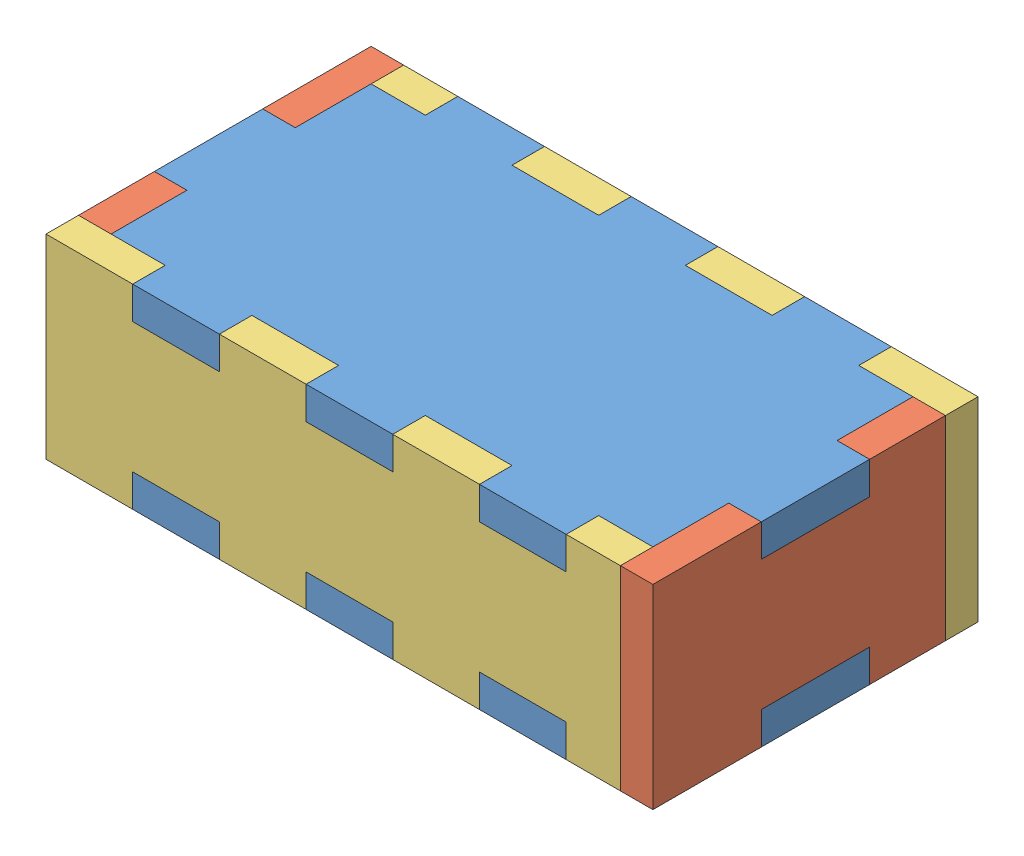
SolidWorks assembly DC-DC CC-CV, configuration Default. Lengths in mm.
Overall size (56 18 30).
6 component instances, 3 part files, 18 mates.
Components (placement in the parent):
- unten_oben-1: unten_oben [unten] at (-9.1679 54.5344 97.0759) size (56 3 30)
- rechts_links-1: rechts_links [rechts] at (46.8327 72.5344 97.0759) x (0 0 -1) z (0 1 0) size (27 3 18)
- vorne_hinten-1: vorne_hinten [Vorne] at (-9.1679 72.5341 97.0759) x (1 0 0) z (0 1 0) size (53 3 18)
- unten_oben-3: unten_oben [oben] at (-9.1679 69.5341 97.0759) size (56 3 30)
- rechts_links-4: rechts_links [links] at (-9.1679 72.5344 67.076) x (0 0 1) z (0 1 0) size (27 3 18)
- vorne_hinten-4: vorne_hinten [Default] at (46.8327 72.5341 67.076) x (-1 0 0) z (0 1 0) size (53 3 18)
Mates (geometry in assembly coordinates):
- Deckungsgleich14: coincident aligned: plane of unten_oben-1 through (-9.1679 57.5344 89.4649) normal (-1 0 0); plane of ? through (-9.1679 123.5344 97.0097) normal (-1 0 0)
- Deckungsgleich17: coincident aligned: plane of unten_oben-1 through (-9.1679 54.5344 97.0759) normal (0 -1 0); plane of ? through (-9.1679 54.5344 51.737) normal (0 -1 0)
- Deckungsgleich19: coincident aligned: plane of unten_oben-1 through (-0.7135 57.5344 97.0097) normal (0 0 1); plane of ? through (-9.1679 62.2019 97.0097) normal (0 0 1)
- Deckungsgleich54: coincident aligned: plane of unten_oben-1 through (-9.1679 54.5344 97.0759) normal (0 -1 0); plane of vorne_hinten-1 through (-9.1679 54.5344 94.0759) normal (0 -1 0)
- Deckungsgleich56: coincident aligned: plane of unten_oben-1 through (-1.1669 57.5344 97.0759) normal (0 0 1); plane of vorne_hinten-1 through (-9.1679 72.5341 97.0759) normal (0 0 1)
- Deckungsgleich57: coincident aligned: plane of vorne_hinten-1 through (-9.1679 72.5341 94.0759) normal (-1 0 0); plane of unten_oben-3 through (-9.1679 72.5341 77.0762) normal (-1 0 0)
- Deckungsgleich58: coincident aligned: plane of vorne_hinten-1 through (-9.1679 72.5341 94.0759) normal (0 1 0); plane of unten_oben-3 through (-9.1679 72.5341 97.0759) normal (0 1 0)
- Deckungsgleich59: coincident aligned: plane of vorne_hinten-1 through (-9.1679 72.5341 97.0759) normal (0 0 1); plane of unten_oben-3 through (-1.1669 72.5341 97.0759) normal (0 0 1)
- Deckungsgleich60: coincident aligned: plane of unten_oben-1 through (46.8327 57.5344 77.0762) normal (1 0 0); plane of rechts_links-1 through (46.8327 72.5344 97.0759) normal (1 0 0)
- Deckungsgleich61: coincident aligned: plane of unten_oben-1 through (-9.1679 54.5344 97.0759) normal (0 -1 0); plane of rechts_links-1 through (43.8327 54.5344 97.0759) normal (0 -1 0)
- Deckungsgleich63: coincident aligned: plane of rechts_links-1 through (43.8327 72.5344 97.0759) normal (0 0 1); plane of vorne_hinten-1 through (-9.1679 72.5341 97.0759) normal (0 0 1)
- Deckungsgleich65: coincident aligned: plane of unten_oben-1 through (-1.1669 57.5344 67.076) normal (0 0 -1); plane of rechts_links-4 through (-6.1679 72.5344 67.076) normal (0 0 -1)
- Deckungsgleich67: coincident aligned: plane of unten_oben-3 through (-9.1679 72.5341 77.0762) normal (-1 0 0); plane of rechts_links-4 through (-9.1679 72.5344 67.076) normal (-1 0 0)
- Deckungsgleich68: coincident aligned: plane of unten_oben-1 through (-9.1679 57.5344 77.0762) normal (-1 0 0); plane of rechts_links-4 through (-9.1679 72.5344 67.076) normal (-1 0 0)
- Deckungsgleich69: coincident aligned: plane of unten_oben-1 through (-9.1679 54.5344 97.0759) normal (0 -1 0); plane of rechts_links-4 through (-6.1679 54.5344 67.076) normal (0 -1 0)
- Deckungsgleich70: coincident aligned: plane of rechts_links-1 through (46.8327 72.5344 97.0759) normal (1 0 0); plane of vorne_hinten-4 through (46.8327 72.5341 70.076) normal (1 0 0)
- Deckungsgleich71: coincident aligned: plane of unten_oben-1 through (30.8325 57.5344 67.076) normal (0 0 -1); plane of vorne_hinten-4 through (46.8327 72.5341 67.076) normal (0 0 -1)
- Deckungsgleich72: coincident aligned: plane of unten_oben-1 through (-9.1679 54.5344 97.0759) normal (0 -1 0); plane of vorne_hinten-4 through (30.8335 54.5344 70.076) normal (0 -1 0)
